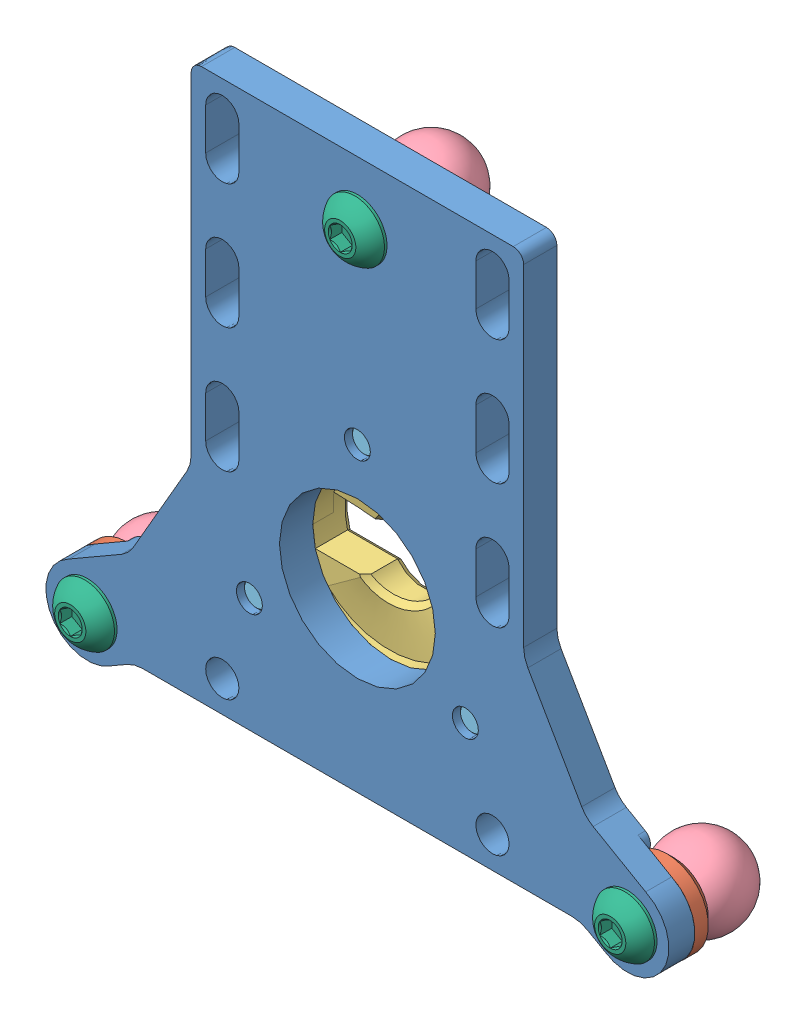
SolidWorks assembly metal_tool_plate_insert, configuration Default. Lengths in mm.
Overall size (63.26 66 12.87).
14 component instances, 6 part files, 24 mates.
Components (placement in the parent):
- coupling_plate_insert-1: coupling_plate_insert [c] at (6.2849 19.7894 28.0883) size (60 66 3.2)
- M3_countersunk_washer_OOTDTY-1: M3_countersunk_washer_OOTDTY [Default] at (32.2656 4.7894 28.0883) x (0.66893 -0.743326 0) z (0.743326 0.66893 0) size (8 2 8)
- M3_countersunk_washer_OOTDTY-2: M3_countersunk_washer_OOTDTY [Default] at (-19.6959 4.7894 28.0883) x (0.66893 -0.743326 0) z (0.743326 0.66893 0) size (8 2 8)
- M3_countersunk_washer_OOTDTY-3: M3_countersunk_washer_OOTDTY [Default] at (6.2849 49.7894 28.0883) x (0.66893 -0.743326 0) z (0.743326 0.66893 0) size (8 2 8)
- wedge_plate-1: wedge_plate [Default] at (6.2849 19.7894 27.3814) x (-1 0 0) z (0 0 1) size (28.78 26 5.61)
- m3_8mm_threaded_ball-1: m3_8mm_threaded_ball [Default] at (6.2849 49.7894 19.4814) x (-0.880671 -0.473728 0) z (0 0 -1) size (8 8 8)
- m3_8mm_threaded_ball-2: m3_8mm_threaded_ball [Default] at (-19.6959 4.7894 19.4814) x (-0.918461 -0.395511 0) z (0 0 -1) size (8 8 8)
- m3_8mm_threaded_ball-3: m3_8mm_threaded_ball [Default] at (32.2656 4.7894 19.4814) x (-0.850254 -0.526372 0) z (0 0 -1) size (8 8 8)
- m3_6mm_flathead_screw_92125A126-1: m3_6mm_flathead_screw_92125A126 [92125A126] at (6.2849 31.7894 23.9314) x (0.331399 -0.943491 0) z (0 0 -1) size (6 6 6.28)
- m3_6mm_flathead_screw_92125A126-2: m3_6mm_flathead_screw_92125A126 [92125A126] at (-4.1075 13.7894 23.9314) x (0.331399 -0.943491 0) z (0 0 -1) size (6 6 6.28)
- m3_6mm_flathead_screw_92125A126-3: m3_6mm_flathead_screw_92125A126 [92125A126] at (16.6772 13.7894 23.9314) x (0.331399 -0.943491 0) z (0 0 -1) size (6 6 6.28)
- m3_6mm_buttonhead_screw_92095A179-1: m3_6mm_buttonhead_screw_92095A179 [92095A179] at (-19.6959 4.7894 32.2383) size (5.7 5.7 7.94)
- m3_6mm_buttonhead_screw_92095A179-2: m3_6mm_buttonhead_screw_92095A179 [92095A179] at (6.2849 49.7894 32.2383) size (5.7 5.7 7.94)
- m3_6mm_buttonhead_screw_92095A179-3: m3_6mm_buttonhead_screw_92095A179 [92095A179] at (32.2656 4.7894 32.2383) size (5.7 5.7 7.94)
Mates (geometry in assembly coordinates):
- Coincident1: coincident anti-aligned: plane of coupling_plate_insert-1 through (6.2849 49.7894 28.0883) normal (0 0 -1); plane of M3_countersunk_washer_OOTDTY-1 through (33.3025 3.6372 28.0883) normal (0 0 1)
- Concentric1: concentric anti-aligned: cylinder of coupling_plate_insert-1 through (32.2656 4.7894 30.8883) axis (0 0 -1) radius 4; circle of M3_countersunk_washer_OOTDTY-1
- Coincident2: coincident anti-aligned: plane of coupling_plate_insert-1 through (6.2849 49.7894 28.0883) normal (0 0 -1); plane of M3_countersunk_washer_OOTDTY-2 through (-18.6591 3.6372 28.0883) normal (0 0 1)
- Concentric2: concentric anti-aligned: cylinder of coupling_plate_insert-1 through (-19.6959 4.7894 30.8883) axis (0 0 -1) radius 4; cylinder of M3_countersunk_washer_OOTDTY-2 through (-19.6959 4.7894 28.0883) axis (0 0 1) radius 4
- Coincident3: coincident anti-aligned: plane of coupling_plate_insert-1 through (6.2849 49.7894 28.0883) normal (0 0 -1); plane of M3_countersunk_washer_OOTDTY-3 through (7.3217 48.6372 28.0883) normal (0 0 1)
- Concentric3: concentric aligned: cylinder of coupling_plate_insert-1 through (6.2849 49.7894 30.8883) axis (0 0 1) radius 1.6; cylinder of M3_countersunk_washer_OOTDTY-3 through (6.2849 49.7894 28.0883) axis (0 0 1) radius 4
- Concentric4: concentric anti-aligned: cylinder of coupling_plate_insert-1 through (6.2849 19.7894 30.8883) axis (0 0 -1) radius 7.5; cylinder of wedge_plate-1 through (6.2849 19.7894 23.7814) axis (0 0 1) radius 3.1
- Concentric5: concentric aligned: cylinder of coupling_plate_insert-1 through (6.2849 49.7894 30.8883) axis (0 0 1) radius 1.6; cylinder of m3_8mm_threaded_ball-1 through (6.2849 49.7894 26.9814) axis (0 0 1) radius 1.25
- Tangent1: tangent aligned: cone of M3_countersunk_washer_OOTDTY-3 through (6.2849 49.7894 26.0883) axis (0 0 1); sphere of m3_8mm_threaded_ball-1
- Concentric6: concentric aligned: cylinder of coupling_plate_insert-1 through (-19.6959 4.7894 30.8883) axis (0 0 1) radius 1.6; cylinder of m3_8mm_threaded_ball-2 through (-19.6959 4.7894 26.9814) axis (0 0 1) radius 1.25
- Tangent2: tangent aligned: cone of M3_countersunk_washer_OOTDTY-2 through (-19.6959 4.7894 26.0883) axis (0 0 1); sphere of m3_8mm_threaded_ball-2
- Concentric7: concentric aligned: cylinder of coupling_plate_insert-1 through (32.2656 4.7894 30.8883) axis (0 0 1) radius 1.6; cylinder of m3_8mm_threaded_ball-3 through (32.2656 4.7894 26.9814) axis (0 0 1) radius 1.25
- Tangent3: tangent aligned: cone of M3_countersunk_washer_OOTDTY-1 through (32.2656 4.7894 26.0883) axis (0 0 1); sphere of m3_8mm_threaded_ball-3
- Distance1: distance = 0.3 mm: line of m3_8mm_threaded_ball-1 through (6.2849 49.7894 23.4814) axis (-0.880671 -0.473728 0); plane of wedge_plate-1 through (6.2849 19.7894 23.7814) normal (0 0 -1)
- Concentric9: concentric aligned: cylinder of coupling_plate_insert-1 through (16.6772 13.7894 28.0883) axis (0 0 -1) radius 1.25; cylinder of wedge_plate-1 through (16.6772 13.7894 23.7814) axis (0 0 -1) radius 1.6
- Coincident4: coincident aligned: cone of wedge_plate-1 through (6.2849 31.7894 23.7814) axis (0 0 1); cone of m3_6mm_flathead_screw_92125A126-1 through (6.2849 31.7894 25.6314) axis (0 0 1)
- Coincident5: coincident aligned: cone of wedge_plate-1 through (-4.1075 13.7894 23.7814) axis (0 0 1); cone of m3_6mm_flathead_screw_92125A126-2 through (-4.1075 13.7894 25.6314) axis (0 0 1)
- Coincident6: coincident aligned: cone of wedge_plate-1 through (16.6772 13.7894 23.7814) axis (0 0 1); cone of m3_6mm_flathead_screw_92125A126-3 through (16.6772 13.7894 25.6314) axis (0 0 1)
- Concentric101: concentric aligned: cylinder of coupling_plate_insert-1 through (-19.6959 4.7894 30.8883) axis (0 0 1) radius 1.6; cylinder of m3_6mm_buttonhead_screw_92095A179-1 through (-19.6959 4.7894 32.2383) axis (0 0 1) radius 2.85
- Coincident71: coincident anti-aligned: plane of coupling_plate_insert-1 through (6.2849 19.7894 30.5883) normal (0 0 1); plane of m3_6mm_buttonhead_screw_92095A179-1 through (-19.6959 1.9394 30.5883) normal (0 0 -1)
- Concentric111: concentric aligned: cylinder of coupling_plate_insert-1 through (6.2849 49.7894 30.8883) axis (0 0 1) radius 1.6; cylinder of m3_6mm_buttonhead_screw_92095A179-2 through (6.2849 49.7894 32.2383) axis (0 0 1) radius 2.85
- Coincident81: coincident anti-aligned: plane of coupling_plate_insert-1 through (6.2849 19.7894 30.5883) normal (0 0 1); plane of m3_6mm_buttonhead_screw_92095A179-2 through (6.2849 46.9394 30.5883) normal (0 0 -1)
- Concentric121: concentric aligned: cylinder of coupling_plate_insert-1 through (32.2656 4.7894 30.8883) axis (0 0 1) radius 1.6; cylinder of m3_6mm_buttonhead_screw_92095A179-3 through (32.2656 4.7894 32.2383) axis (0 0 1) radius 2.85
- Coincident91: coincident anti-aligned: plane of coupling_plate_insert-1 through (6.2849 19.7894 30.5883) normal (0 0 1); plane of m3_6mm_buttonhead_screw_92095A179-3 through (32.2656 1.9394 30.5883) normal (0 0 -1)
